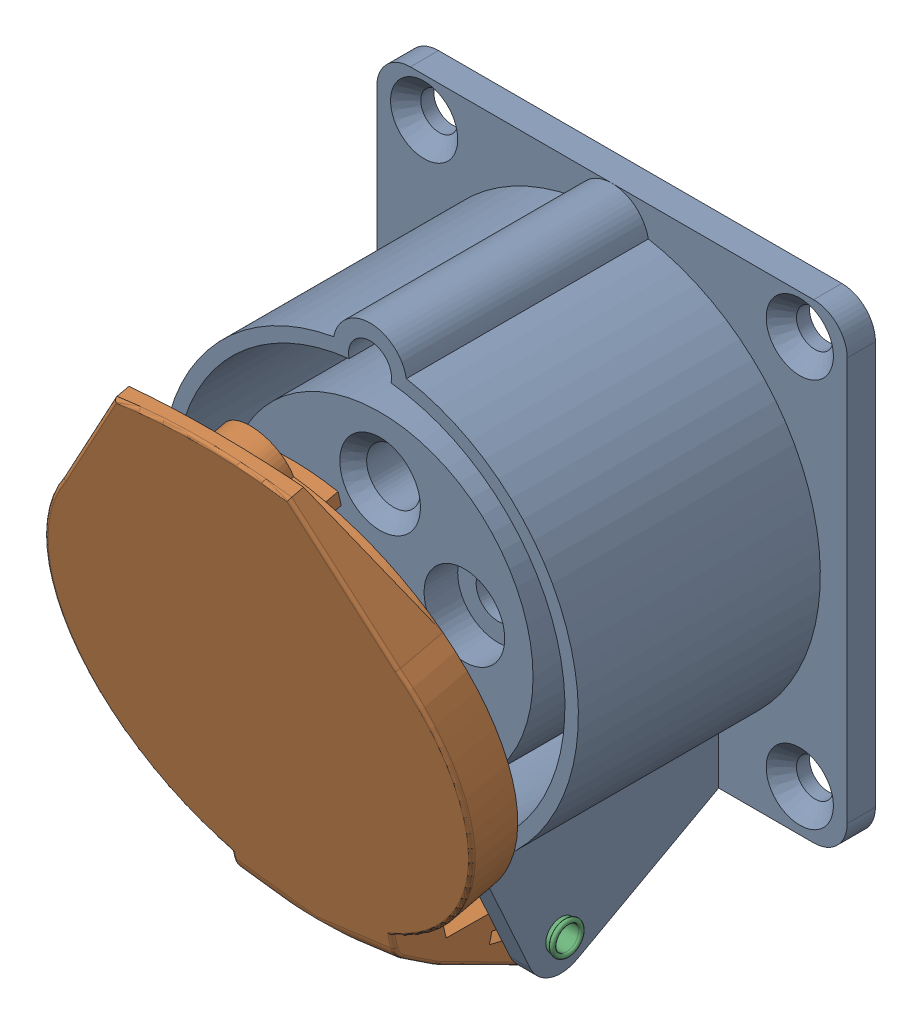
SolidWorks assembly 0-202, configuration Default. Lengths in mm.
Overall size (70 89.01 67.82).
3 component instances, 3 part files, 5 mates.
Components (placement in the parent):
- 1-004-1: 1-004 [Default] at origin size (70 82.16 42.9)
- 1-005-2: 1-005 [Default] at (0 -39.0637 43.5711) x (-1 0 0) z (0 0.228171 -0.973621) size (62 85.67 24.56)
- 1-008-1: 1-008 [Default] at (-15.7249 -39.2316 23.4726) x (0 -0.843891 0.536515) z (0 0.536515 0.843891) size (4.9 32.3 4.9)
Mates (geometry in assembly coordinates):
- Concentric12: concentric aligned: cylinder of 1-004-1 through (-12 -39.2316 23.4726) axis (-1 0 0) radius 2; cylinder of 1-005-2 through (12 -39.2316 23.4726) axis (-1 0 0) radius 2
- Parallel2: parallel anti-aligned: line of 1-004-1 through (-12 -42.8957 19.7541) axis (1 0 0); line of 1-005-2 through (11.5 -43.6941 25.7278) axis (-1 0 0)
- Concentric13: concentric aligned: cylinder of 1-004-1 through (-12 -39.2316 23.4726) axis (-1 0 0) radius 2; cylinder of 1-008-1 through (-15.7249 -39.2316 23.4726) axis (-1 0 0) radius 1.75
- Lock3: lock: unknown of 1-004-1; unknown of 1-008-1
- Coincident12: coincident anti-aligned: plane of 1-004-1 through (-12 0 0) normal (1 0 0); plane of 1-005-2 through (-12 -39.2316 23.4726) normal (-1 0 0)
